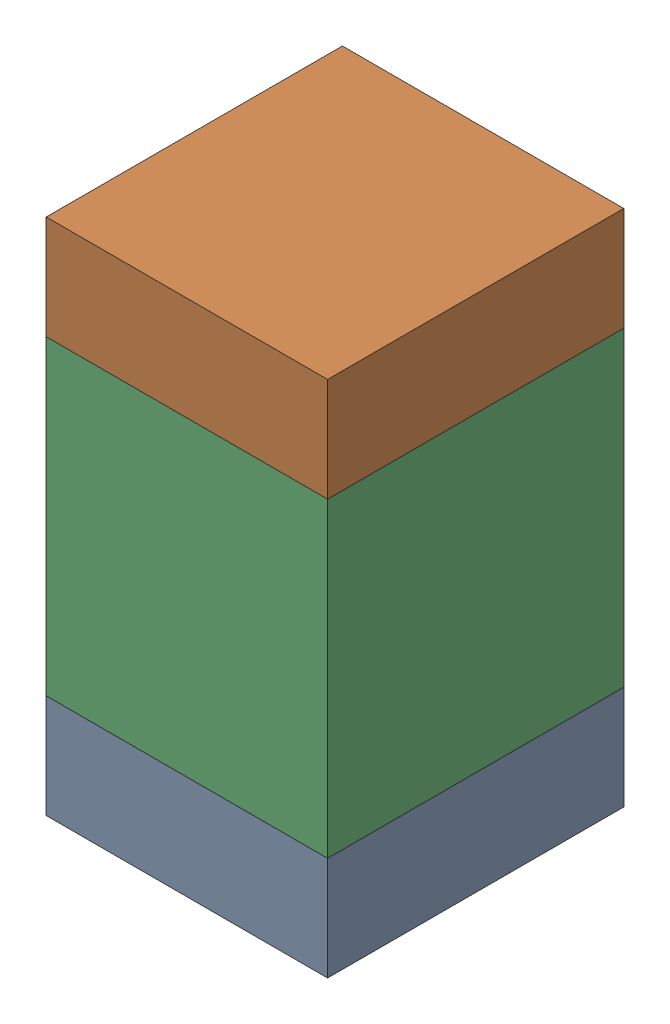
SolidWorks assembly C11, configuration Default. Lengths in mm.
Overall size (0.95 1.75 1).
6 component instances, 2 part files, 0 mates.
Components (placement in the parent):
- 959208664-1: 959208664 [Default] at (122.4827 75.652 0) size (0.95 0.35 1)
  - Extruded-14-1: Extruded-14 [Default] at origin size (0.95 0.35 1)
- 959208664-2: 959208664 [Default] at (122.4827 77.052 0) size (0.95 0.35 1)
  - Extruded-14-1: Extruded-14 [Default] at origin size (0.95 0.35 1)
- 959208528-1: 959208528 [Default] at (122.4827 76.352 0) size (0.95 1.05 1)
  - Extruded-15-1: Extruded-15 [Default] at origin size (0.95 1.05 1)
